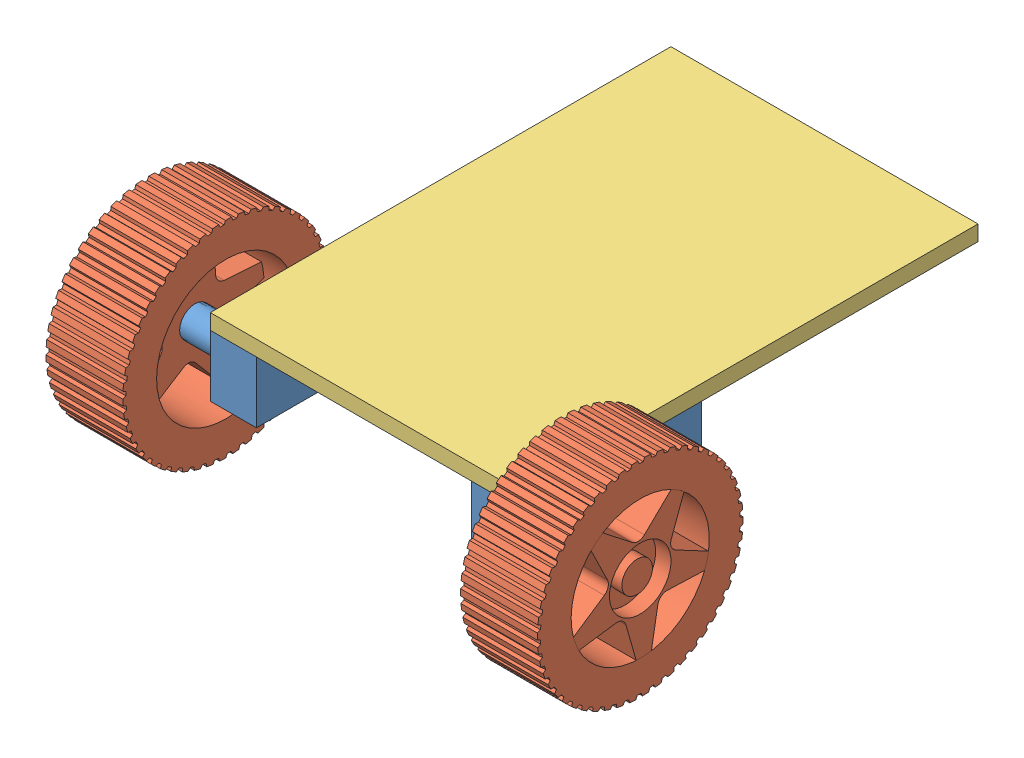
SolidWorks assembly Car, configuration Default. Lengths in mm.
Overall size (160 82.05 181.03).
5 component instances, 3 part files, 8 mates.
Components (placement in the parent):
- Motor-1: Motor [Default] at (25.8562 28.9444 73.7528) size (30 20 60)
- Wheel-1: Wheel [Default] at (40.8562 28.9444 73.7528) x (0 -0.965912 0.258871) z (1 0 0) size (66.99 67 25)
- Plate-2: Plate [Default] at (10.8562 38.9444 83.7528) x (0 0 1) z (-1 0 0) size (150 5 100)
- Motor-2: Motor [Default] at (-104.1438 28.9444 73.7528) x (-1 0 0) z (0 0 1) size (30 20 60)
- Wheel-2: Wheel [Default] at (-119.1438 28.9444 73.7528) x (0 0.152912 0.98824) z (-1 0 0) size (66.99 67 25)
Mates (geometry in assembly coordinates):
- Coincident2: coincident anti-aligned: circle of Motor-1; circle of Wheel-1
- Coincident3: coincident: point of Motor-1; point of Plate-2
- Coincident5: coincident: point of Motor-1; plane of Plate-2 through (10.8562 38.9444 -66.2472) normal (0 -1 0)
- Coincident6: coincident: point of Motor-1; line of Plate-2 through (10.8562 38.9444 -66.2472) axis (0 0 1)
- Coincident7: coincident anti-aligned: circle of Motor-2; circle of Wheel-2
- Coincident8: coincident: point of Plate-2; point of Motor-2
- Coincident9: coincident: plane of Plate-2 through (10.8562 38.9444 -66.2472) normal (0 -1 0); point of Motor-2
- Coincident10: coincident: line of Plate-2 through (-89.1438 38.9444 83.7528) axis (1 0 0); point of Motor-2
